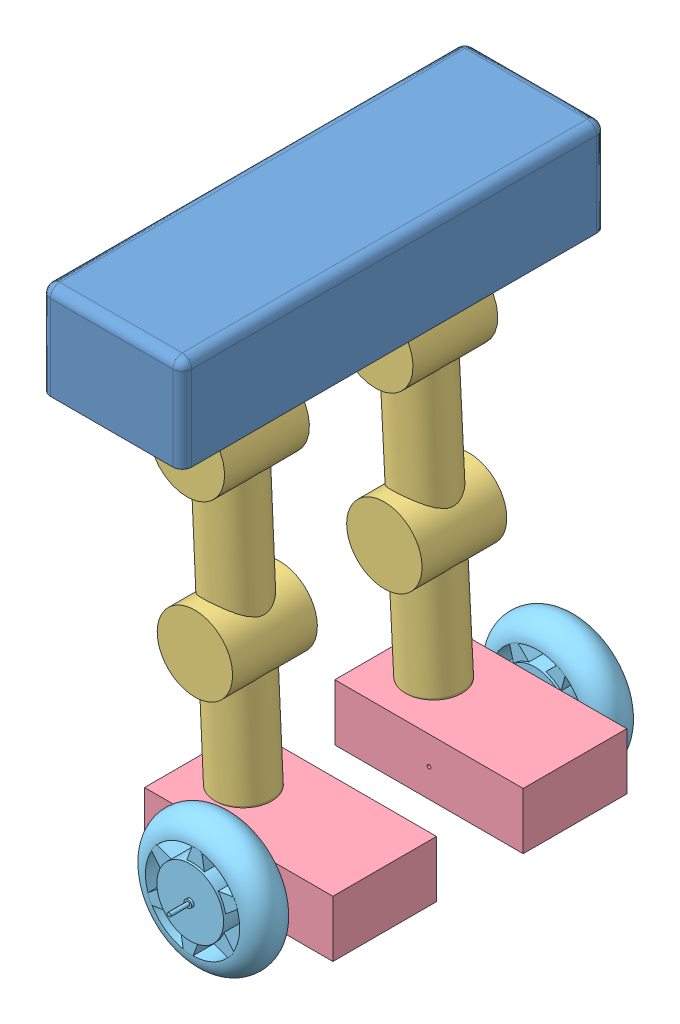
SolidWorks assembly Assem-11, configuration Default. Lengths in mm.
Overall size (24.2 60.87 45.8).
9 component instances, 5 part files, 20 mates.
Components (placement in the parent):
- Part1-2: Part1 [Default] at (3.4987 28.6931 34.0618) x (0 0 -1) z (1 0 0) size (45 10 15)
- Part2-2: Part2 [Default] at (10.9987 15.1931 24.0618) x (-1 0 0) z (0 0 -1) size (6 6.59 6)
- Part2-3: Part2 [Default] at (10.9987 15.1931 44.0618) x (-1 0 0) z (0 0 -1) size (6 6.59 6)
- Part3-1: Part3 [Default] at (10.9987 15.1931 44.0618) x (0.998912 0.046637 0) z (0 0 1) size (8 39 9)
- Part3-2: Part3 [Default] at (10.9987 15.1931 24.0618) x (0.998596 0.052973 0) z (0 0 1) size (8 39 9)
- Part4-5: Part4 [Default] at (17.491 -22.772 44.0618) size (20 6 11)
- Part4-6: Part4 [Default] at (17.6938 -22.7619 24.0618) size (20 6 11)
- wheels-1: wheels [Default] at (17.491 -19.772 52.2618) x (0.815134 -0.579273 0) z (0 0 1) size (14.2 14.2 9.4)
- wheels-2: wheels [Default] at (17.6938 -19.7619 15.8618) size (14.2 14.2 9.4)
Mates (geometry in assembly coordinates):
- Concentric1: concentric: sphere of Part1-2; sphere of Part2-3
- Concentric2: concentric: sphere of Part1-2; sphere of Part2-2
- Lock1: lock: unknown of Part1-2; unknown of Part2-3
- Lock2: lock: unknown of Part1-2; unknown of Part2-2
- Concentric3: concentric aligned: cylinder of Part2-3 through (10.9987 15.1931 47.0618) axis (0 0 -1) radius 4; cylinder of Part3-1 through (10.9987 15.1931 48.5618) axis (0 0 -1) radius 4
- Distance1: distance = 8 mm aligned: plane of Part1-2 through (18.4987 21.1931 56.5618) normal (0 0 1); plane of Part3-1 through (10.9987 15.1931 48.5618) normal (0 0 1)
- Concentric4: concentric aligned: cylinder of Part2-2 through (10.9987 15.1931 27.0618) axis (0 0 -1) radius 4; cylinder of Part3-2 through (10.9987 15.1931 28.5618) axis (0 0 -1) radius 4
- Distance2: distance = 8 mm aligned: plane of Part3-2 through (10.9987 15.1931 19.5618) normal (0 0 -1); plane of Part1-2 through (18.4987 21.1931 11.5618) normal (0 0 -1)
- Concentric10: concentric: sphere of Part3-1; sphere of Part4-5
- Parallel12: parallel aligned: plane of Part1-2 through (18.4987 21.1931 56.5618) normal (0 0 1); plane of Part4-5 through (7.491 -16.772 49.5618) normal (0 0 1)
- Parallel13: parallel aligned: plane of Part1-2 through (3.4987 31.1931 34.0618) normal (0 1 0); plane of Part4-5 through (17.491 -16.772 44.0618) normal (0 1 0)
- Concentric11: concentric: sphere of Part3-2; sphere of Part4-6
- Parallel14: parallel aligned: plane of Part1-2 through (3.4987 31.1931 34.0618) normal (0 1 0); plane of Part4-6 through (17.6938 -16.7619 24.0618) normal (0 1 0)
- Parallel15: parallel aligned: plane of Part1-2 through (18.4987 21.1931 56.5618) normal (0 0 1); plane of Part4-6 through (7.6938 -16.7619 29.5618) normal (0 0 1)
- LimitDistance1: limit distance = 8.9924 mm aligned: plane of Part4-5 through (27.491 -16.772 49.5618) normal (1 0 0); plane of Part1-2 through (18.4987 28.6931 34.0618) normal (1 0 0)
- LimitDistance2: limit distance = 9.1951 mm aligned: plane of Part4-6 through (27.6938 -16.7619 29.5618) normal (1 0 0); plane of Part1-2 through (18.4987 28.6931 34.0618) normal (1 0 0)
- Coincident1: coincident aligned: circle of Part4-5; cylinder of wheels-1 through (17.491 -19.772 58.5271) axis (0 0 1) radius 0.2
- Coincident2: coincident anti-aligned: plane of Part4-5 through (7.491 -16.772 49.5618) normal (0 0 1); plane of wheels-1 through (17.491 -19.772 49.5618) normal (0 0 -1)
- Coincident4: coincident aligned: circle of Part4-6; cylinder of wheels-2 through (17.6938 -19.7619 22.1271) axis (0 0 1) radius 0.2
- Coincident5: coincident anti-aligned: plane of Part4-6 through (7.6938 -16.7619 18.5618) normal (0 0 -1); plane of wheels-2 through (17.6938 -19.7619 18.5618) normal (0 0 1)
